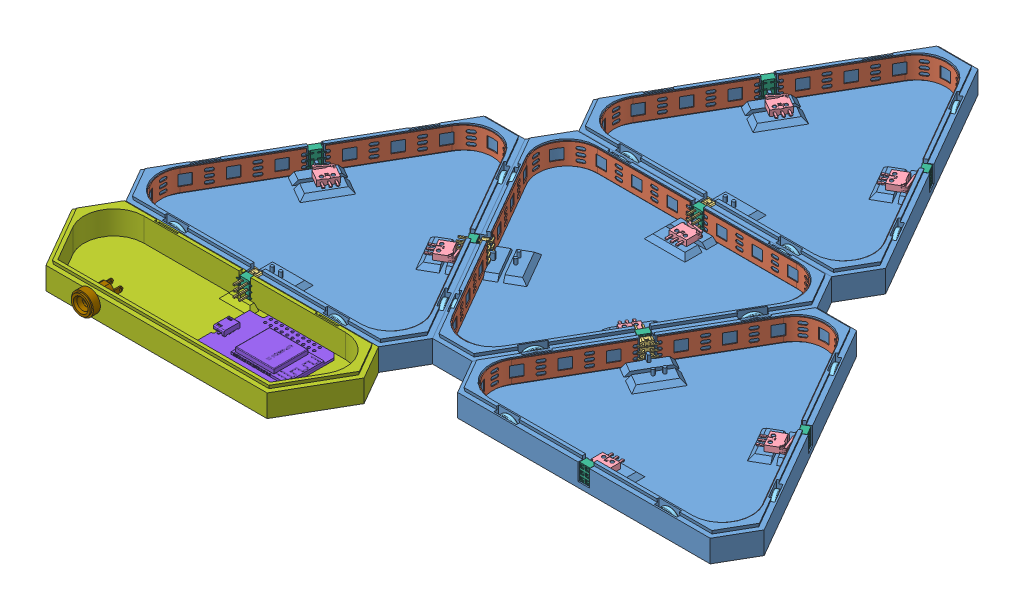
SolidWorks assembly nanoleaf_21leds_multi, configuration Défaut. Lengths in mm.
Overall size (329.34 14.05 341.96).
75 component instances, 12 part files, 12 mates.
Components (placement in the parent):
- nanoleaf_21leds-1: nanoleaf_21leds [Défaut] at (-32.3609 -8.2691 146.7938) size (136.52 14.05 135.13)
  - nanoleaf_21leds_bottom-1: nanoleaf_21leds_bottom [Défaut] at origin size (136.52 12 118.23)
  - nanoleaf_21leds_top-1: nanoleaf_21leds_top [Défaut] at (0 13 0) x (1 0 0) z (0 0 -1) size (136.52 3 118.23) (hidden)
  - Strip_led_ws2812_60leds-m-1: Strip_led_ws2812_60leds-m [Défaut] at (-91.3022 6.5 75.6507) x (0.5 0 -0.866025) z (0.866025 0 0.5) size (57.63 10 59.04)
  - Strip_led_ws2812_60leds-m-2: Strip_led_ws2812_60leds-m [Défaut] at (111.1665 6.5 41.2446) x (-1 0 0) z (0 0 -1) size (57.63 10 59.04)
  - Strip_led_ws2812_60leds-m-3: Strip_led_ws2812_60leds-m [Défaut] at (-19.8643 6.5 -116.8953) x (0.5 0 0.866025) z (-0.866025 0 0.5) size (57.63 10 59.04)
  - TSM_103_02_T_DV-1: TSM_103_02_T_DV [Défaut] at (0 6.5 42.7496) x (0 -1 0) z (-1 0 0) size (7.62 11.94 7.44)
  - TS0101F020P-1: TS0101F020P [Défaut] at (29.5407 4.35 -15.3233) x (-0.5 0 -0.866025) z (0.866025 0 -0.5) size (8.31 2.7 12.18)
  - TS0101F020P-5: TS0101F020P [Défaut] at (-28.0407 4.35 -17.9214) x (-0.5 0 0.866025) z (-0.866025 0 -0.5) size (8.31 2.7 12.18)
  - Aimant_10x2mm-1: Aimant_10x2mm [Défaut] at (37.5 6 41.7446) x (0.78482 -0.619723 0) z (0 0 1) size (10 10 2)
  - Aimant_10x2mm-2: Aimant_10x2mm [Défaut] at (-37.5 6 41.9446) x (0.873152 -0.487449 0) z (0 0 1) size (10 10 2)
  - Aimant_10x2mm-4: Aimant_10x2mm [Défaut] at (-55.0751 6 11.5036) x (-0.272453 -0.838497 0.471903) z (-0.866025 0 -0.5) size (10 10 2)
  - Aimant_10x2mm-6: Aimant_10x2mm [Défaut] at (-17.5751 6 -53.4483) x (-0.128011 -0.966671 0.221722) z (-0.866025 0 -0.5) size (10 10 2)
  - Aimant_10x2mm-8: Aimant_10x2mm [Défaut] at (17.5751 6 -53.4483) x (-0.4998 -0.028255 -0.86568) z (0.866025 0 -0.5) size (10 10 2)
  - Aimant_10x2mm-10: Aimant_10x2mm [Défaut] at (55.0751 6 11.5036) x (-0.49797 -0.09001 -0.86251) z (0.866025 0 -0.5) size (10 10 2)
  - 610006243021-1: 610006243021 [Défaut] at (-36.888 6.5 -21.2973) x (0 1 0) z (-0.866025 0 -0.5) size (7.62 7.21 3.7)
  - 610006243021-2: 610006243021 [Défaut] at (36.888 6.5 -21.2973) x (0 1 0) z (0.866025 0 -0.5) size (7.62 7.21 3.7)
- nanoleaf_21leds-2: nanoleaf_21leds [Défaut] at (45.1391 -8.2691 102.0491) x (0.5 0 0.866025) z (-0.866025 0 0.5) size (136.52 14.05 135.13)
  - nanoleaf_21leds_bottom-1: nanoleaf_21leds_bottom [Défaut] at origin size (136.52 12 118.23)
  - nanoleaf_21leds_top-1: nanoleaf_21leds_top [Défaut] at (0 13 0) x (1 0 0) z (0 0 -1) size (136.52 3 118.23) (hidden)
  - Strip_led_ws2812_60leds-m-1: Strip_led_ws2812_60leds-m [Défaut] at (-91.3022 6.5 75.6507) x (0.5 0 -0.866025) z (0.866025 0 0.5) size (57.63 10 59.04)
  - Strip_led_ws2812_60leds-m-2: Strip_led_ws2812_60leds-m [Défaut] at (111.1665 6.5 41.2446) x (-1 0 0) z (0 0 -1) size (57.63 10 59.04)
  - Strip_led_ws2812_60leds-m-3: Strip_led_ws2812_60leds-m [Défaut] at (-19.8643 6.5 -116.8953) x (0.5 0 0.866025) z (-0.866025 0 0.5) size (57.63 10 59.04)
  - TSM_103_02_T_DV-1: TSM_103_02_T_DV [Défaut] at (0 6.5 42.7496) x (0 -1 0) z (-1 0 0) size (7.62 11.94 7.44)
  - TS0101F020P-1: TS0101F020P [Défaut] at (29.5407 4.35 -15.3233) x (-0.5 0 -0.866025) z (0.866025 0 -0.5) size (8.31 2.7 12.18)
  - TS0101F020P-5: TS0101F020P [Défaut] at (-28.0407 4.35 -17.9214) x (-0.5 0 0.866025) z (-0.866025 0 -0.5) size (8.31 2.7 12.18)
  - Aimant_10x2mm-1: Aimant_10x2mm [Défaut] at (37.5 6 41.7446) x (0.78482 -0.619723 0) z (0 0 1) size (10 10 2)
  - Aimant_10x2mm-2: Aimant_10x2mm [Défaut] at (-37.5 6 41.9446) x (0.873152 -0.487449 0) z (0 0 1) size (10 10 2)
  - Aimant_10x2mm-4: Aimant_10x2mm [Défaut] at (-55.0751 6 11.5036) x (-0.272453 -0.838497 0.471903) z (-0.866025 0 -0.5) size (10 10 2)
  - Aimant_10x2mm-6: Aimant_10x2mm [Défaut] at (-17.5751 6 -53.4483) x (-0.128011 -0.966671 0.221722) z (-0.866025 0 -0.5) size (10 10 2)
  - Aimant_10x2mm-8: Aimant_10x2mm [Défaut] at (17.5751 6 -53.4483) x (-0.4998 -0.028255 -0.86568) z (0.866025 0 -0.5) size (10 10 2)
  - Aimant_10x2mm-10: Aimant_10x2mm [Défaut] at (55.0751 6 11.5036) x (-0.49797 -0.09001 -0.86251) z (0.866025 0 -0.5) size (10 10 2)
  - 610006243021-1: 610006243021 [Défaut] at (-36.888 6.5 -21.2973) x (0 1 0) z (-0.866025 0 -0.5) size (7.62 7.21 3.7)
  - 610006243021-2: 610006243021 [Défaut] at (36.888 6.5 -21.2973) x (0 1 0) z (0.866025 0 -0.5) size (7.62 7.21 3.7)
- nanoleaf_21leds-3: nanoleaf_21leds [Défaut] at (122.6391 -8.2691 146.7938) x (-0.5 0 0.866025) z (-0.866025 0 -0.5) size (136.52 14.05 135.13)
  - nanoleaf_21leds_bottom-1: nanoleaf_21leds_bottom [Défaut] at origin size (136.52 12 118.23)
  - nanoleaf_21leds_top-1: nanoleaf_21leds_top [Défaut] at (0 13 0) x (1 0 0) z (0 0 -1) size (136.52 3 118.23) (hidden)
  - Strip_led_ws2812_60leds-m-1: Strip_led_ws2812_60leds-m [Défaut] at (-91.3022 6.5 75.6507) x (0.5 0 -0.866025) z (0.866025 0 0.5) size (57.63 10 59.04)
  - Strip_led_ws2812_60leds-m-2: Strip_led_ws2812_60leds-m [Défaut] at (111.1665 6.5 41.2446) x (-1 0 0) z (0 0 -1) size (57.63 10 59.04)
  - Strip_led_ws2812_60leds-m-3: Strip_led_ws2812_60leds-m [Défaut] at (-19.8643 6.5 -116.8953) x (0.5 0 0.866025) z (-0.866025 0 0.5) size (57.63 10 59.04)
  - TSM_103_02_T_DV-1: TSM_103_02_T_DV [Défaut] at (0 6.5 42.7496) x (0 -1 0) z (-1 0 0) size (7.62 11.94 7.44)
  - TS0101F020P-1: TS0101F020P [Défaut] at (29.5407 4.35 -15.3233) x (-0.5 0 -0.866025) z (0.866025 0 -0.5) size (8.31 2.7 12.18)
  - TS0101F020P-5: TS0101F020P [Défaut] at (-28.0407 4.35 -17.9214) x (-0.5 0 0.866025) z (-0.866025 0 -0.5) size (8.31 2.7 12.18)
  - Aimant_10x2mm-1: Aimant_10x2mm [Défaut] at (37.5 6 41.7446) x (0.78482 -0.619723 0) z (0 0 1) size (10 10 2)
  - Aimant_10x2mm-2: Aimant_10x2mm [Défaut] at (-37.5 6 41.9446) x (0.873152 -0.487449 0) z (0 0 1) size (10 10 2)
  - Aimant_10x2mm-4: Aimant_10x2mm [Défaut] at (-55.0751 6 11.5036) x (-0.272453 -0.838497 0.471903) z (-0.866025 0 -0.5) size (10 10 2)
  - Aimant_10x2mm-6: Aimant_10x2mm [Défaut] at (-17.5751 6 -53.4483) x (-0.128011 -0.966671 0.221722) z (-0.866025 0 -0.5) size (10 10 2)
  - Aimant_10x2mm-8: Aimant_10x2mm [Défaut] at (17.5751 6 -53.4483) x (-0.4998 -0.028255 -0.86568) z (0.866025 0 -0.5) size (10 10 2)
  - Aimant_10x2mm-10: Aimant_10x2mm [Défaut] at (55.0751 6 11.5036) x (-0.49797 -0.09001 -0.86251) z (0.866025 0 -0.5) size (10 10 2)
  - 610006243021-1: 610006243021 [Défaut] at (-36.888 6.5 -21.2973) x (0 1 0) z (-0.866025 0 -0.5) size (7.62 7.21 3.7)
  - 610006243021-2: 610006243021 [Défaut] at (36.888 6.5 -21.2973) x (0 1 0) z (0.866025 0 -0.5) size (7.62 7.21 3.7)
- nanoleaf_21leds-4: nanoleaf_21leds [Défaut] at (45.1391 -8.2691 12.5598) size (136.52 14.05 135.13)
  - nanoleaf_21leds_bottom-1: nanoleaf_21leds_bottom [Défaut] at origin size (136.52 12 118.23)
  - nanoleaf_21leds_top-1: nanoleaf_21leds_top [Défaut] at (0 13 0) x (1 0 0) z (0 0 -1) size (136.52 3 118.23) (hidden)
  - Strip_led_ws2812_60leds-m-1: Strip_led_ws2812_60leds-m [Défaut] at (-91.3022 6.5 75.6507) x (0.5 0 -0.866025) z (0.866025 0 0.5) size (57.63 10 59.04)
  - Strip_led_ws2812_60leds-m-2: Strip_led_ws2812_60leds-m [Défaut] at (111.1665 6.5 41.2446) x (-1 0 0) z (0 0 -1) size (57.63 10 59.04)
  - Strip_led_ws2812_60leds-m-3: Strip_led_ws2812_60leds-m [Défaut] at (-19.8643 6.5 -116.8953) x (0.5 0 0.866025) z (-0.866025 0 0.5) size (57.63 10 59.04)
  - TSM_103_02_T_DV-1: TSM_103_02_T_DV [Défaut] at (0 6.5 42.7496) x (0 -1 0) z (-1 0 0) size (7.62 11.94 7.44)
  - TS0101F020P-1: TS0101F020P [Défaut] at (29.5407 4.35 -15.3233) x (-0.5 0 -0.866025) z (0.866025 0 -0.5) size (8.31 2.7 12.18)
  - TS0101F020P-5: TS0101F020P [Défaut] at (-28.0407 4.35 -17.9214) x (-0.5 0 0.866025) z (-0.866025 0 -0.5) size (8.31 2.7 12.18)
  - Aimant_10x2mm-1: Aimant_10x2mm [Défaut] at (37.5 6 41.7446) x (0.78482 -0.619723 0) z (0 0 1) size (10 10 2)
  - Aimant_10x2mm-2: Aimant_10x2mm [Défaut] at (-37.5 6 41.9446) x (0.873152 -0.487449 0) z (0 0 1) size (10 10 2)
  - Aimant_10x2mm-4: Aimant_10x2mm [Défaut] at (-55.0751 6 11.5036) x (-0.272453 -0.838497 0.471903) z (-0.866025 0 -0.5) size (10 10 2)
  - Aimant_10x2mm-6: Aimant_10x2mm [Défaut] at (-17.5751 6 -53.4483) x (-0.128011 -0.966671 0.221722) z (-0.866025 0 -0.5) size (10 10 2)
  - Aimant_10x2mm-8: Aimant_10x2mm [Défaut] at (17.5751 6 -53.4483) x (-0.4998 -0.028255 -0.86568) z (0.866025 0 -0.5) size (10 10 2)
  - Aimant_10x2mm-10: Aimant_10x2mm [Défaut] at (55.0751 6 11.5036) x (-0.49797 -0.09001 -0.86251) z (0.866025 0 -0.5) size (10 10 2)
  - 610006243021-1: 610006243021 [Défaut] at (-36.888 6.5 -21.2973) x (0 1 0) z (-0.866025 0 -0.5) size (7.62 7.21 3.7)
  - 610006243021-2: 610006243021 [Défaut] at (36.888 6.5 -21.2973) x (0 1 0) z (0.866025 0 -0.5) size (7.62 7.21 3.7)
- nanoleaf_controller-1: nanoleaf_controller [Défaut] at (-32.3609 -8.2691 236.283) size (149.44 12 140.61)
  - nanoleaf_controller_bottom-1: nanoleaf_controller_bottom [Défaut] x (0.5 0 -0.866025) z (0.866025 0 0.5) size (94.1 12 118.23)
  - nanoleaf_controller_top-1: nanoleaf_controller_top [Défaut] at (0 14 0) x (1 0 0) z (0 -1 0) size (136.52 44.74 3.5) (hidden)
  - ESP32_Mini_full-1: ESP32_Mini_full [Défaut] at (27.1805 3 -22.6762) x (0 0 1) z (-1 0 0) size (31.2 4 39)
  - DC Jack Panel Mount Base-1: DC Jack Panel Mount Base [Default] at (-31.3429 6.5 3.3) size (10.2 10.2 17.63)
  - 610006243021-1: 610006243021 [Défaut] at (0 6.5 -42.7626) x (0 1 0) z (0 0 -1) size (7.62 7.21 3.7)
  - 61300625721-1: 61300625721 [Défaut] at (0 6.5 -43.5034) x (0 -1 0) z (0 0 -1) size (8.22 5.33 8.1) (hidden)
Mates (geometry in assembly coordinates):
- Coïncidente1: coincident: plane of nanoleaf_21leds-1/nanoleaf_21leds_bottom-1 through (-32.3609 -8.2691 146.7938) normal (0 -1 0); plane of nanoleaf_21leds-2/nanoleaf_21leds_bottom-1 through (45.1391 -8.2691 102.0491) normal (0 -1 0)
- Coïncidente2: coincident: plane of nanoleaf_21leds-1/nanoleaf_21leds_bottom-1 through (45.1391 3.7309 191.5384) normal (0.866025 0 -0.5); plane of nanoleaf_21leds-2/nanoleaf_21leds_bottom-1 through (-32.3609 3.7309 57.3045) normal (-0.866025 0 0.5)
- Coïncidente3: coincident: plane of nanoleaf_21leds-1/nanoleaf_21leds_bottom-1 through (-32.3609 -8.2691 146.7938) normal (0.5 0 0.866025); plane of nanoleaf_21leds-2/nanoleaf_21leds_bottom-1 through (45.1391 -8.2691 102.0491) normal (-0.5 0 -0.866025)
- Coïncidente4: coincident: plane of nanoleaf_21leds-1/nanoleaf_21leds_bottom-1 through (-32.3609 -8.2691 146.7938) normal (0 -1 0); plane of nanoleaf_21leds-3/nanoleaf_21leds_bottom-1 through (122.6391 -8.2691 146.7938) normal (0 -1 0)
- Coïncidente5: coincident: plane of nanoleaf_21leds-2/nanoleaf_21leds_bottom-1 through (45.1391 3.7309 191.5384) normal (0.866025 0 0.5); plane of nanoleaf_21leds-3/nanoleaf_21leds_bottom-1 through (122.6391 3.7309 57.3045) normal (-0.866025 0 -0.5)
- Coïncidente6: coincident: plane of nanoleaf_21leds-2/nanoleaf_21leds_bottom-1 through (45.1391 -8.2691 102.0491) normal (-0.5 0 0.866025); plane of nanoleaf_21leds-3/nanoleaf_21leds_bottom-1 through (122.6391 -8.2691 146.7938) normal (0.5 0 -0.866025)
- Coïncidente7: coincident: plane of nanoleaf_21leds-1/nanoleaf_21leds_bottom-1 through (-32.3609 -8.2691 146.7938) normal (0 -1 0); plane of nanoleaf_21leds-4/nanoleaf_21leds_bottom-1 through (45.1391 -8.2691 12.5598) normal (0 -1 0)
- Coïncidente9: coincident: plane of nanoleaf_21leds-2/nanoleaf_21leds_bottom-1 through (45.1391 -8.2691 102.0491) normal (-1 0 0); plane of nanoleaf_21leds-4/nanoleaf_21leds_bottom-1 through (45.1391 -8.2691 12.5598) normal (-1 0 0)
- Coïncidente11: coincident: plane of nanoleaf_21leds-2/nanoleaf_21leds_bottom-1 through (122.6391 3.7309 57.3045) normal (0 0 -1); plane of nanoleaf_21leds-4/nanoleaf_21leds_bottom-1 through (-32.3609 3.7309 57.3045) normal (0 0 1)
- Coïncidente12: coincident: plane of nanoleaf_21leds-1/nanoleaf_21leds_bottom-1 through (-109.8609 3.7309 191.5384) normal (0 0 1); plane of nanoleaf_controller-1/nanoleaf_controller_bottom-1 through (45.1391 3.7309 191.5384) normal (0 0 -1)
- Coïncidente13: coincident: plane of nanoleaf_21leds-1/nanoleaf_21leds_bottom-1 through (-32.3609 -8.2691 146.7938) normal (0 -1 0); plane of nanoleaf_controller-1/nanoleaf_controller_bottom-1 through (-32.3609 -8.2691 236.283) normal (0 -1 0)
- Coïncidente14: coincident: plane of nanoleaf_21leds-1/nanoleaf_21leds_bottom-1 through (-32.3609 -8.2691 146.7938) normal (1 0 0); plane of nanoleaf_controller-1 through (-32.3609 -8.2691 236.283) normal (1 0 0)
